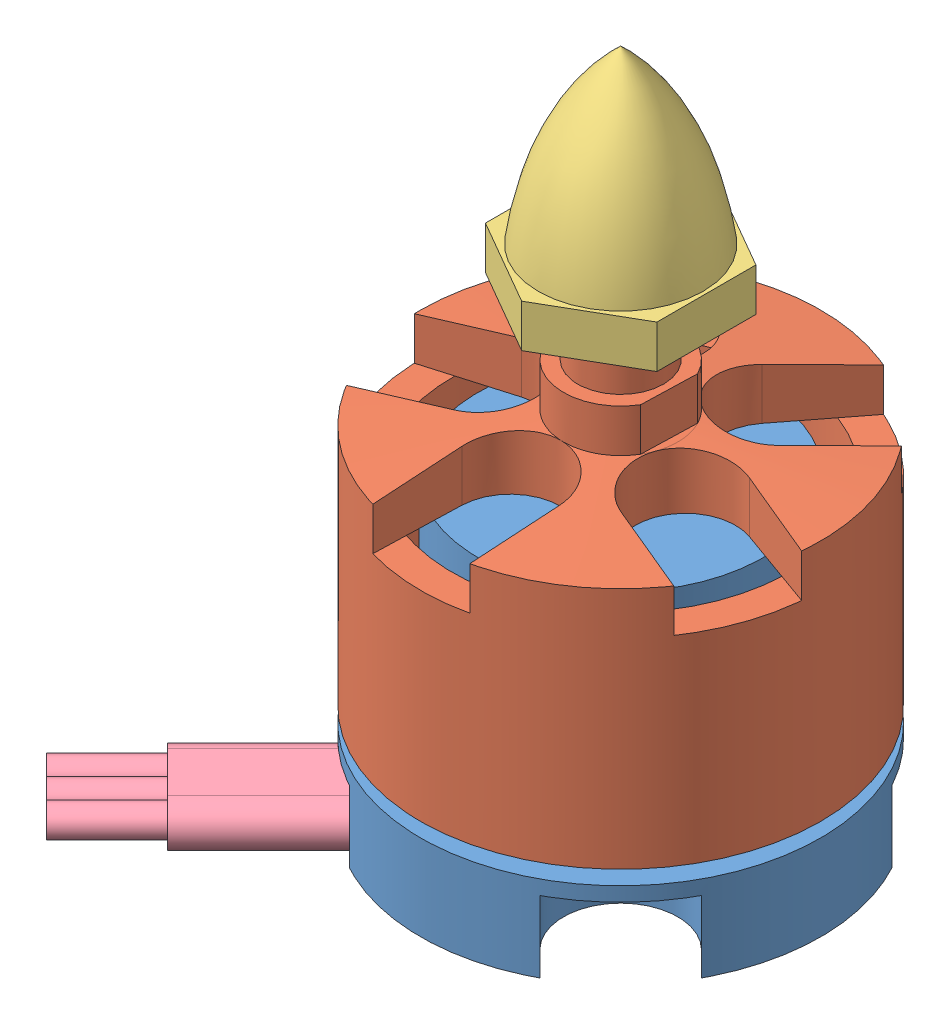
SolidWorks assembly User Library-emaxmodel-mt2213, configuration По умолчанию. Lengths in mm.
Overall size (36.98 47 36.98).
4 component instances, 4 part files, 7 mates.
Components (placement in the parent):
- User Library-emaxmodel-mt2213_emaxmodel-mt2213-stator-1: User Library-emaxmodel-mt2213_emaxmodel-mt2213-stator [По умолчанию] at origin size (28 21 28)
- User Library-emaxmodel-mt2213_emaxmodel-mt2213-rotor-1: User Library-emaxmodel-mt2213_emaxmodel-mt2213-rotor [По умолчанию] at (0 7 0) x (0.999557 0 0.02976) z (-0.02976 0 0.999557) size (28 32 28)
- User Library-emaxmodel-mt2213_emaxmodel-mt2213-cone-1: User Library-emaxmodel-mt2213_emaxmodel-mt2213-cone [По умолчанию] at (0 32 0) size (12 15 13.86)
- User Library-emaxmodel-mt2213_wires-1: User Library-emaxmodel-mt2213_wires [По умолчанию] at (-15.8508 1.5 15.8508) x (0.707107 0 0.707107) z (-0.707107 0 0.707107) size (7 3 19)
Mates (geometry in assembly coordinates):
- Концентричный1: concentric: cylinder of User Library-emaxmodel-mt2213_emaxmodel-mt2213-stator-1 through (0 6 0) axis (0 -1 0) radius 14; cylinder of User Library-emaxmodel-mt2213_emaxmodel-mt2213-rotor-1 through (0 21 0) axis (0 -1 0) radius 14
- Расстояние1: distance = 39 mm: plane of User Library-emaxmodel-mt2213_emaxmodel-mt2213-stator-1 through (0 0 0) normal (0 -1 0); plane of User Library-emaxmodel-mt2213_emaxmodel-mt2213-rotor-1 through (0 39 0) normal (0 1 0)
- Концентричный2: concentric: cylinder of User Library-emaxmodel-mt2213_emaxmodel-mt2213-rotor-1 through (0 39 0) axis (0 -1 0) radius 3; point of User Library-emaxmodel-mt2213_emaxmodel-mt2213-cone-1
- Расстояние2: distance = 4 mm: plane of User Library-emaxmodel-mt2213_emaxmodel-mt2213-cone-1 through (0 32 0) normal (0 -1 0); plane of User Library-emaxmodel-mt2213_emaxmodel-mt2213-rotor-1 through (0 28 0) normal (0 1 0)
- Совпадение3: coincident: plane of User Library-emaxmodel-mt2213_emaxmodel-mt2213-stator-1 through (0 0 0) normal (0 -1 0); plane of User Library-emaxmodel-mt2213_wires-1 through (-5.2442 0 8.0726) normal (0 -1 0)
- Расстояние3: distance = 0.5 mm: plane of User Library-emaxmodel-mt2213_emaxmodel-mt2213-stator-1 through (-9.6764 5 15.3332) normal (-0.707107 0 -0.707107); cylinder of User Library-emaxmodel-mt2213_wires-1 through (-5.2442 1.5 8.0726) axis (-0.707107 0 0.707107) radius 1.5
- Расстояние4: distance = 9 mm: plane of User Library-emaxmodel-mt2213_wires-1 through (-14.4366 1.5 17.265) normal (-0.707107 0 0.707107); line of User Library-emaxmodel-mt2213_emaxmodel-mt2213-stator-1 through (-6.6584 5 12.3153) axis (0 -1 0)
